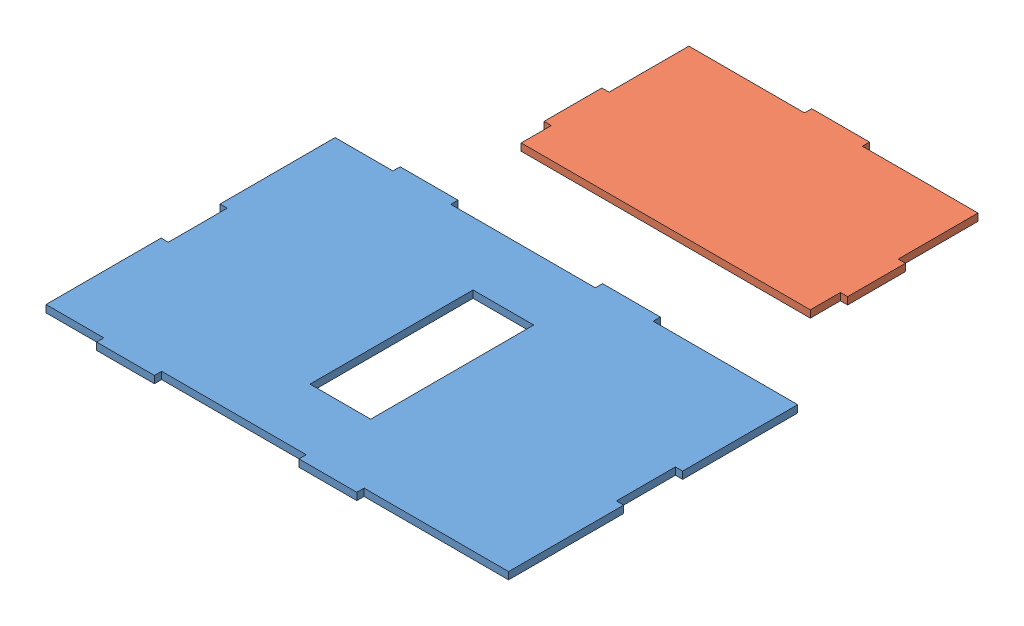
SolidWorks assembly Sheet 3, configuration Default. Lengths in mm.
Overall size (210 745.98 280).
2 component instances, 2 part files, 0 mates.
Components (placement in the parent):
- Top-1: Top [Default] at (-24.912 843.175 138.3644) size (203.2 3.17 133.35)
- Front-1: Front [Default] at (77.1552 841.5875 60.4707) x (0 0 -1) z (1 0 0) size (76.83 3.17 133.35)
